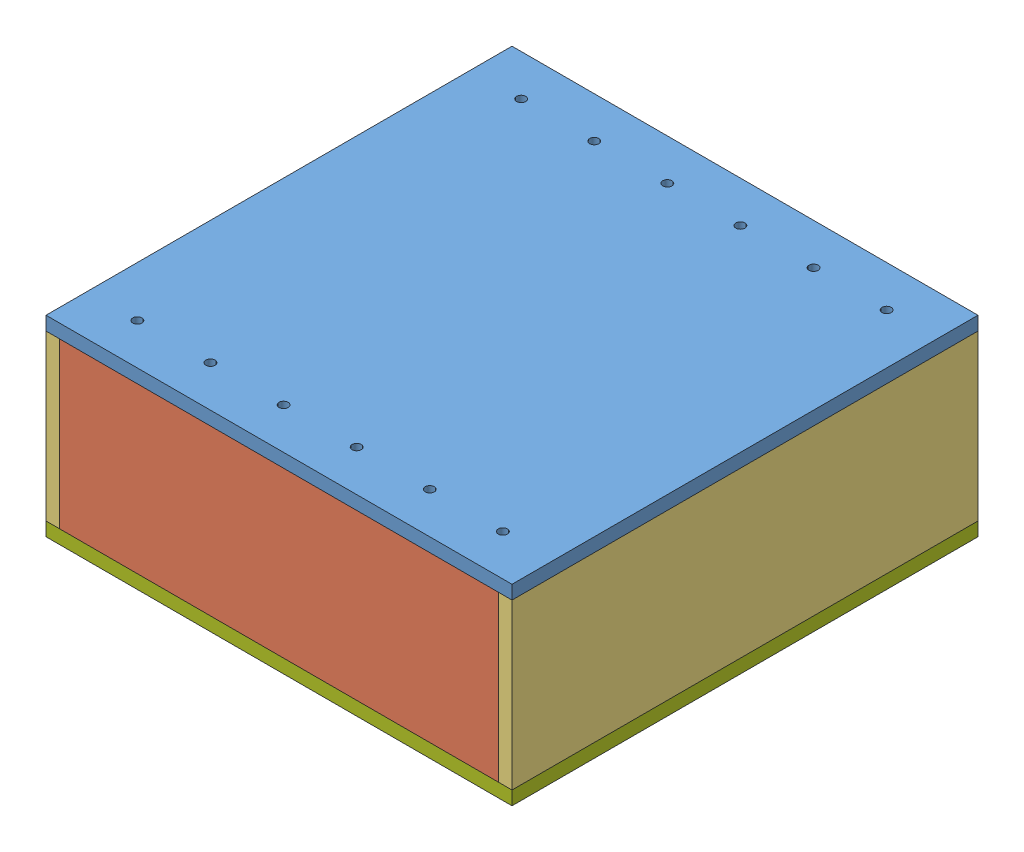
SolidWorks assembly asMold, configuration Default. Lengths in mm.
Overall size (647.7 266.7 647.7).
12 component instances, 7 part files, 30 mates.
Components (placement in the parent):
- top-2: top [Default] at (-247.2798 -5.2911 -238.5676) size (647.7 19.05 647.7)
- side-3: side [Default] at (-228.2298 -5.2911 390.0824) size (609.6 228.6 19.05)
- side-4: side [Default] at (-228.2298 -5.2911 -238.5676) size (609.6 228.6 19.05)
- frontBack-3: frontBack [Default] at (381.3702 -5.2911 409.1324) size (19.05 228.6 647.7)
- frontBack-4: frontBack [Default] at (-247.2798 -5.2911 409.1324) size (19.05 228.6 647.7)
- innerSide-3: innerSide [Default] at (-152.0298 -113.2411 390.0824) x (0 0 -1) z (1 0 0) size (609.6 107.95 19.05)
- innerSide-4: innerSide [Default] at (305.1702 -113.2411 -219.5176) x (0 0 1) z (-1 0 0) size (609.6 107.95 19.05)
- innerBott-2: innerBott [Default] at (305.1702 -132.2911 -219.5176) x (0 0 1) z (-1 0 0) size (609.6 19.05 457.2)
- innerSupp-1: innerSupp [Default] at (-132.9798 -113.2411 -186.6192) x (0 0 1) z (-1 0 0) size (19.05 107.95 419.1)
- innerSupp-2: innerSupp [Default] at (-132.9798 -113.2411 47.0473) x (0 0 1) z (-1 0 0) size (19.05 107.95 419.1)
- innerSupp-3: innerSupp [Default] at (-132.9798 -113.2411 262.5803) x (0 0 1) z (-1 0 0) size (19.05 107.95 419.1)
- bottom-2: bottom [Default] at (-247.2798 -252.9411 -238.5676) size (647.7 19.05 647.7)
Mates (geometry in assembly coordinates):
- Coincident29: coincident anti-aligned: plane of top-2 through (-247.2798 -5.2911 409.1324) normal (0 -1 0); plane of frontBack-3 through (400.4202 -5.2911 409.1324) normal (0 1 0)
- Coincident30: coincident aligned: plane of top-2 through (-247.2798 13.7589 409.1324) normal (0 0 1); plane of frontBack-3 through (400.4202 -5.2911 409.1324) normal (0 0 1)
- Coincident31: coincident aligned: plane of top-2 through (400.4202 13.7589 -238.5676) normal (1 0 0); plane of frontBack-3 through (400.4202 -233.8911 409.1324) normal (1 0 0)
- Coincident32: coincident anti-aligned: plane of top-2 through (-247.2798 -5.2911 409.1324) normal (0 -1 0); plane of side-4 through (-228.2298 -5.2911 -219.5176) normal (0 1 0)
- Coincident33: coincident anti-aligned: plane of side-4 through (381.3702 -5.2911 -219.5176) normal (1 0 0); plane of frontBack-3 through (381.3702 -233.8911 409.1324) normal (-1 0 0)
- Coincident34: coincident aligned: plane of top-2 through (-247.2798 13.7589 -238.5676) normal (0 0 -1); plane of side-4 through (-228.2298 -233.8911 -238.5676) normal (0 0 -1)
- Coincident35: coincident anti-aligned: plane of top-2 through (-247.2798 -5.2911 409.1324) normal (0 -1 0); plane of frontBack-4 through (-228.2298 -5.2911 409.1324) normal (0 1 0)
- Coincident38: coincident aligned: plane of side-4 through (-228.2298 -233.8911 -238.5676) normal (0 0 -1); plane of frontBack-4 through (-228.2298 -5.2911 -238.5676) normal (0 0 -1)
- Coincident39: coincident anti-aligned: plane of side-4 through (-228.2298 -5.2911 -219.5176) normal (-1 0 0); plane of frontBack-4 through (-228.2298 -233.8911 409.1324) normal (1 0 0)
- Coincident40: coincident anti-aligned: plane of side-3 through (-228.2298 -5.2911 409.1324) normal (-1 0 0); plane of frontBack-4 through (-228.2298 -233.8911 409.1324) normal (1 0 0)
- Coincident41: coincident anti-aligned: plane of top-2 through (-247.2798 -5.2911 409.1324) normal (0 -1 0); plane of side-3 through (-228.2298 -5.2911 409.1324) normal (0 1 0)
- Coincident42: coincident aligned: plane of top-2 through (-247.2798 13.7589 409.1324) normal (0 0 1); plane of side-3 through (-228.2298 -233.8911 409.1324) normal (0 0 1)
- Coincident43: coincident anti-aligned: plane of side-3 through (-228.2298 -233.8911 390.0824) normal (0 0 -1); plane of innerSide-3 through (-132.9798 -5.2911 390.0824) normal (0 0 1)
- Coincident44: coincident anti-aligned: plane of top-2 through (-247.2798 -5.2911 409.1324) normal (0 -1 0); plane of innerSide-3 through (-132.9798 -5.2911 390.0824) normal (0 1 0)
- Distance4: distance = 76.2 mm anti-aligned: plane of innerSide-3 through (-152.0298 -113.2411 390.0824) normal (-1 0 0); plane of frontBack-4 through (-228.2298 -233.8911 409.1324) normal (1 0 0)
- Coincident47: coincident anti-aligned: plane of top-2 through (-247.2798 -5.2911 409.1324) normal (0 -1 0); plane of innerSide-4 through (286.1202 -5.2911 -219.5176) normal (0 1 0)
- Coincident48: coincident anti-aligned: plane of side-3 through (-228.2298 -233.8911 390.0824) normal (0 0 -1); plane of innerSide-4 through (286.1202 -5.2911 390.0824) normal (0 0 1)
- Distance5: distance = 76.2 mm anti-aligned: plane of innerSide-4 through (305.1702 -113.2411 -219.5176) normal (1 0 0); plane of frontBack-3 through (381.3702 -233.8911 409.1324) normal (-1 0 0)
- Coincident50: coincident anti-aligned: plane of innerSide-3 through (-132.9798 -113.2411 390.0824) normal (1 0 0); plane of innerSupp-3 through (-132.9798 -5.2911 281.6303) normal (-1 0 0)
- Coincident51: coincident anti-aligned: plane of top-2 through (-247.2798 -5.2911 409.1324) normal (0 -1 0); plane of innerSupp-3 through (-132.9798 -5.2911 281.6303) normal (0 1 0)
- Coincident52: coincident anti-aligned: plane of innerSide-3 through (-132.9798 -113.2411 390.0824) normal (1 0 0); plane of innerSupp-2 through (-132.9798 -5.2911 66.0973) normal (-1 0 0)
- Coincident53: coincident anti-aligned: plane of top-2 through (-247.2798 -5.2911 409.1324) normal (0 -1 0); plane of innerSupp-2 through (-132.9798 -5.2911 66.0973) normal (0 1 0)
- Coincident54: coincident anti-aligned: plane of innerSide-3 through (-132.9798 -113.2411 390.0824) normal (1 0 0); plane of innerSupp-1 through (-132.9798 -5.2911 -167.5692) normal (-1 0 0)
- Coincident55: coincident anti-aligned: plane of top-2 through (-247.2798 -5.2911 409.1324) normal (0 -1 0); plane of innerSupp-1 through (-132.9798 -5.2911 -167.5692) normal (0 1 0)
- Coincident56: coincident anti-aligned: plane of innerSide-3 through (-132.9798 -113.2411 390.0824) normal (0 -1 0); plane of innerBott-2 through (-152.0298 -113.2411 -219.5176) normal (0 1 0)
- Coincident57: coincident anti-aligned: plane of side-3 through (-228.2298 -233.8911 390.0824) normal (0 0 -1); plane of innerBott-2 through (305.1702 -113.2411 390.0824) normal (0 0 1)
- Coincident58: coincident aligned: plane of innerSide-4 through (305.1702 -113.2411 -219.5176) normal (1 0 0); plane of innerBott-2 through (305.1702 -113.2411 -219.5176) normal (1 0 0)
- Coincident59: coincident anti-aligned: plane of side-4 through (-228.2298 -233.8911 -219.5176) normal (0 -1 0); plane of bottom-2 through (-247.2798 -233.8911 409.1324) normal (0 1 0)
- Coincident60: coincident aligned: plane of frontBack-3 through (400.4202 -233.8911 409.1324) normal (1 0 0); plane of bottom-2 through (400.4202 -233.8911 -238.5676) normal (1 0 0)
- Coincident61: coincident aligned: plane of side-3 through (-228.2298 -233.8911 409.1324) normal (0 0 1); plane of bottom-2 through (-247.2798 -233.8911 409.1324) normal (0 0 1)
